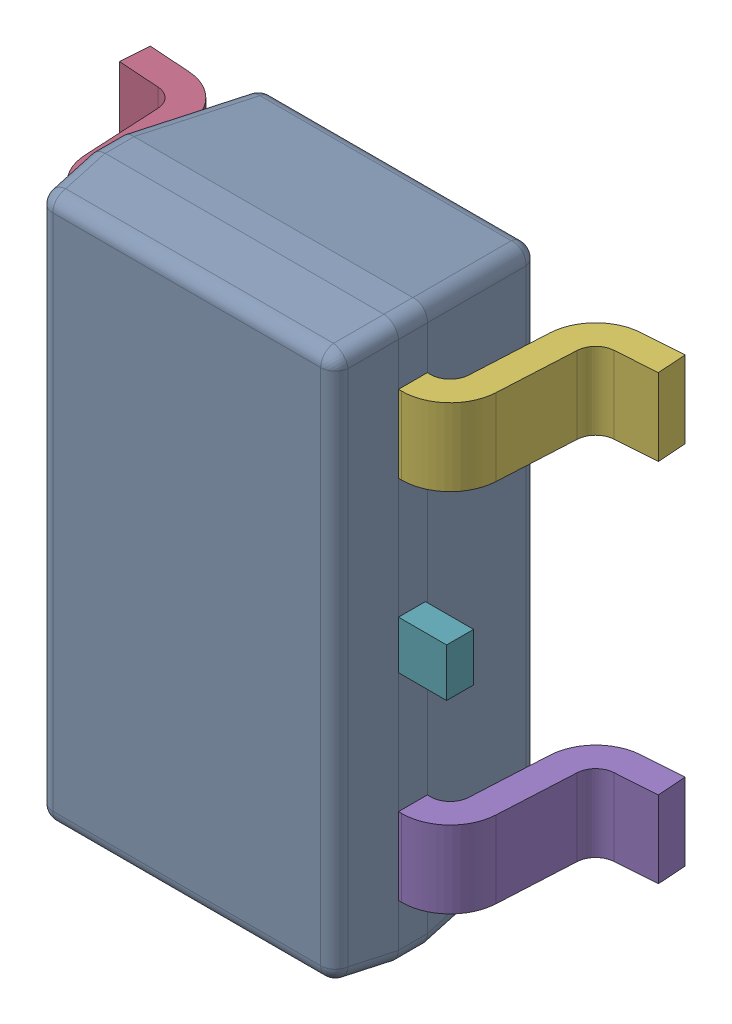
SolidWorks assembly IC19_1.step, configuration Default. Lengths in mm.
Overall size (2.8 2.9 1.2).
8 component instances, 3 part files, 0 mates.
Components (placement in the parent):
- 6348793248_1.step-3: 6348793248_1.step [Default] at (394.3455 305.0466 0) x (1 0 0) z (0 0 1) size (2.8 2.9 1.2)
  - BODY-SOT_1.step-3: BODY-SOT_1.step [Default] at (0 0 0.9) x (0 -1 0) z (-1 0 0) size (2.9 1.1 1.6)
  - LEAD-SOT_1.step-11: LEAD-SOT_1.step [Default] at (-0.9395 -0.95 0.25) x (0 -1 0) z (-1 0 0) size (0.4 0.9 0.6)
  - LEAD-SOT_1.step-12: LEAD-SOT_1.step [Default] at (-0.9395 0 0.25) x (0 -1 0) z (-1 0 0) size (0.4 0.9 0.6)
  - LEAD-SOT_1.step-13: LEAD-SOT_1.step [Default] at (-0.9395 0.95 0.25) x (0 -1 0) z (-1 0 0) size (0.4 0.9 0.6)
  - LEAD-SOT_1.step-14: LEAD-SOT_1.step [Default] at (0.9395 -0.95 0.25) x (0 1 0) z (1 0 0) size (0.4 0.9 0.6)
  - LEAD-SOT_1.step-15: LEAD-SOT_1.step [Default] at (0.9395 0.95 0.25) x (0 1 0) z (1 0 0) size (0.4 0.9 0.6)
  - LEAD-DUMMY_1.step-3: LEAD-DUMMY_1.step [Default] at (1.05 0 0.76) x (0 -1 0) z (-1 0 0) size (0.25 0.14 0.25)
